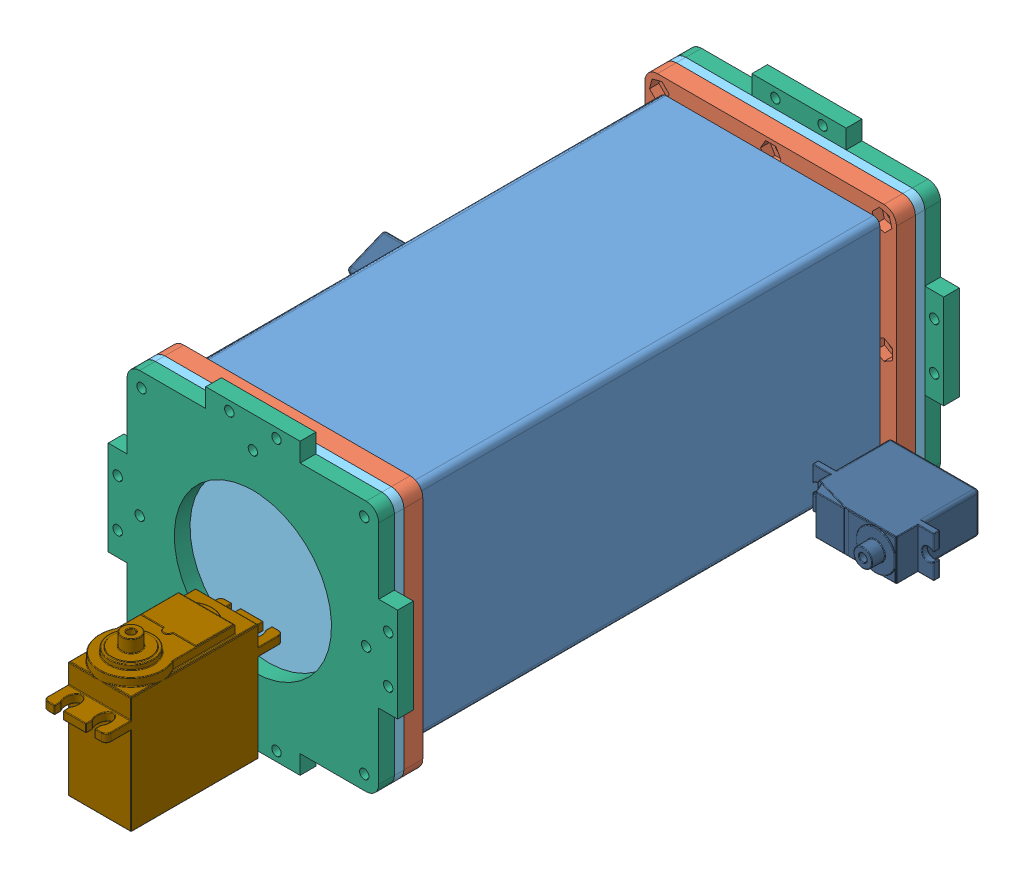
SolidWorks assembly 装载物件图, configuration 默认. Lengths in mm.
Overall size (147.1 92 234.4).
20 component instances, 10 part files, 7 mates.
Components (placement in the parent):
- 方形密封舱-1: 方形密封舱 [默认] at (-13.9625 1.8792 -42) size (92.6 92 178)
  - 密封舱-亚克力段70-1: 密封舱-亚克力段70 [默认] at (7.5922 -1.2732 140) size (70 70 150)
  - 矩形法兰70708080-1: 矩形法兰70708080 [默认] at (7.2922 -1.5732 290) x (1 0 0) z (0 -1 0) size (80 26.9 80)
  - 矩形法兰70708080-2: 矩形法兰70708080 [默认] at (7.8922 -1.5732 140) x (1 0 0) z (0 1 0) size (80 26.9 80)
  - 3.55矩形氟橡胶-1: 3.55矩形氟橡胶 [默认] at (7.8833 -1.3232 145.6959) x (0 1 0) z (0.00069 0 -1) size (64.79 64.74 4.92)
  - 3.55矩形氟橡胶-2: 3.55矩形氟橡胶 [默认] at (7.3995 -1.2605 277.2066) size (64.79 64.74 4.92)
  - 3.55矩形氟橡胶-3: 3.55矩形氟橡胶 [默认] at (6.8133 -1.5822 284.2743) size (64.79 64.74 4.92)
  - 3.55矩形氟橡胶-4: 3.55矩形氟橡胶 [默认] at (7.7739 -1.2858 153.0152) size (64.79 64.74 4.92)
  - 60氟橡胶圈-1: 60氟橡胶圈 [默认] at (7.8922 -1.5732 135.6037) x (0.95369 0.300791 0) z (-0.300791 0.95369 0) size (67.1 3.55 67.1)
  - 60氟橡胶圈-2: 60氟橡胶圈 [默认] at (7.2922 -1.5732 297.7537) x (0.472409 0.881379 0) z (-0.881379 0.472409 0) size (67.1 3.55 67.1)
  - 矩形法兰盖80803-1: 矩形法兰盖80803 [默认] at (7.8922 -1.5732 134) x (1 0 0) z (0 1 0) size (80 3 80)
  - 矩形法兰盖80803-2: 矩形法兰盖80803 [默认] at (7.2922 -1.5732 299) x (1 0 0) z (0 1 0) size (80 3 80)
  - 矩形法兰保护框-1: 矩形法兰保护框 [默认] at (7.8922 -1.5732 131) x (1 0 0) z (0 1 0) size (92 5 92)
  - 矩形法兰保护框-2: 矩形法兰保护框 [默认] at (7.2922 -1.5732 304) x (1 0 0) z (0 1 0) size (92 5 92)
- 内部构建-1: 内部构建 [默认] at (-7.7769 18.8215 27.1) size (60 60 105)
  - 电路板-1: 电路板 [默认] at (-0.5934 -6.2155 100) size (60 40 100)
  - 重心调节器-1: 重心调节器 [默认] at (-18.1276 -37.4051 95) x (0 -1 0) z (0 0 1) size (20 42.85 105)
- PDI-6221mg-180-1: PDI-6221mg-180 [默认] at (-6.9366 -39.694 290.2) x (0 0 1) z (0 1 0) size (56.4 20 45.2)
- es 3004-1: es 3004 [默认] at (-60.6453 5.8416 158.2765) x (-1 0 0) z (0 -0.924225 -0.381849) size (38.55 13 31.1)
- es 3004-2: es 3004 [默认] at (47.9047 -27.5615 99.7075) size (38.55 13 31.1)
Mates (geometry in assembly coordinates):
- 重合2: coincident: plane of assembly; plane of assembly; plane of 方形密封舱-1/密封舱-亚克力段70-1 through (-38.3703 32.606 248) normal (1 0 0); plane of 内部构建-1/重心调节器-1 through (-38.3703 -27.394 212.1) normal (-1 0 0)
- 重合3: coincident: plane of assembly; plane of assembly; plane of 方形密封舱-1/矩形法兰70708080-1 through (-6.6703 0.306 227.1) normal (0 0 -1); plane of 内部构建-1/电路板-1 through (-8.3703 12.606 227.1) normal (0 0 1)
- 重合4: coincident: plane of assembly; plane of assembly; plane of 方形密封舱-1/密封舱-亚克力段70-1 through (-38.3703 32.606 248) normal (0 -1 0); plane of 内部构建-1/电路板-1 through (-38.3703 32.606 227.1) normal (0 1 0)
- 重合6: coincident: plane of assembly; plane of assembly; plane of 方形密封舱-1/矩形法兰保护框-2 through (-6.6703 0.306 262) normal (0 0 1); plane of PDI-6221mg-180-1 through (-10.5768 -9.094 262) normal (0 0 -1)
- 重合7: coincident: plane of assembly; plane of assembly; plane of 方形密封舱-1/矩形法兰保护框-2 through (-46.6703 -39.694 257) normal (0 -1 0); plane of PDI-6221mg-180-1 through (-6.9366 -39.694 290.2) normal (0 -1 0)
- 重合8: coincident: plane of assembly; plane of assembly; plane of 方形密封舱-1/密封舱-亚克力段70-1 through (28.6297 35.606 248) normal (1 0 0); plane of es 3004-2 through (28.6297 -34.0615 119.4075) normal (-1 0 0)
- 重合9: coincident: plane of assembly; plane of assembly; plane of 方形密封舱-1/密封舱-亚克力段70-1 through (-41.3703 35.606 248) normal (-1 0 0); plane of es 3004-1 through (-41.3703 -11.974 149.8062) normal (1 0 0)
